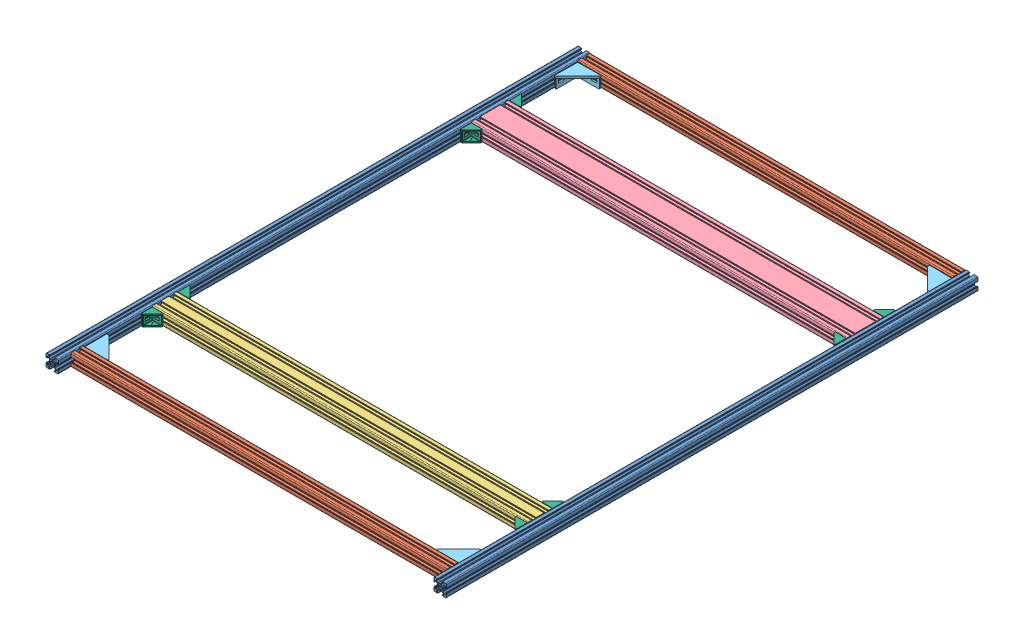
SolidWorks assembly SideAluminum, configuration Default. Lengths in mm.
Overall size (640 20.19 850).
18 component instances, 6 part files, 51 mates.
Components (placement in the parent):
- Profile 20x20-850mm-1: Profile 20x20-850mm [Default] at (265.7213 429.4124 252.9994) size (20 20 850)
- Profile 20x20-600mm-1: Profile 20x20-600mm [Default] at (884.2213 429.4124 254.4994) x (0 0 1) z (-1 0 0) size (20 20 600)
- Profile 20x20-850mm-2: Profile 20x20-850mm [Default] at (902.7213 449.4124 252.9994) x (-1 0 0) z (0 0 1) size (20 20 850)
- Profile 20x20-600mm-2: Profile 20x20-600mm [Default] at (284.2213 429.4124 1081.4994) x (0 0 -1) z (1 0 0) size (20 20 600)
- Profile 20x40-600m-1: Profile 20x40-600m [Default] at (884.2213 429.4124 926.6994) x (0 0 1) z (-1 0 0) size (40 20 600)
- Profile 20x60-600mm-1: Profile 20x60-600mm [Default] at (1884.2213 429.4124 396.6994) x (0 0 1) z (-1 0 0) size (60 20 600)
- Bracket 20x40-1: Bracket 20x40 [Default] at (284.2213 438.4124 272.9994) x (0 0 -1) z (0 -1 0) size (39.5 39.5 18)
- Bracket 20x40-2: Bracket 20x40 [Default] at (884.2213 438.4124 272.9994) x (1 0 0) z (0 -1 0) size (39.5 39.5 18)
- Bracket 20x40-3: Bracket 20x40 [Default] at (284.2213 438.4124 1062.9994) x (-1 0 0) z (0 -1 0) size (39.5 39.5 18)
- Bracket 20x40-4: Bracket 20x40 [Default] at (884.2213 438.4124 1062.9994) x (0 0 1) z (0 -1 0) size (39.5 39.5 18)
- Bracket 20x20-1: Bracket 20x20 [Default] at (284.2213 439.7182 382.9994) x (0 0 1) z (0 1 0) size (19.8 19.8 18)
- Bracket 20x20-2: Bracket 20x20 [Default] at (884.2213 439.7182 382.9994) x (1 0 0) z (0 1 0) size (19.8 19.8 18)
- Bracket 20x20-3: Bracket 20x20 [Default] at (884.2213 440.6035 442.9994) x (1 0 0) z (0 -1 0) size (19.8 19.8 18)
- Bracket 20x20-4: Bracket 20x20 [Default] at (284.2213 439.2066 442.9994) x (-1 0 0) z (0 1 0) size (19.8 19.8 18)
- Bracket 20x20-5: Bracket 20x20 [Default] at (284.2213 439.7182 912.9994) x (0 0 1) z (0 1 0) size (19.8 19.8 18)
- Bracket 20x20-6: Bracket 20x20 [Default] at (284.2213 439.2066 952.9994) x (0 0 -1) z (0 -1 0) size (19.8 19.8 18)
- Bracket 20x20-7: Bracket 20x20 [Default] at (884.2213 439.7182 912.9994) x (1 0 0) z (0 1 0) size (19.8 19.8 18)
- Bracket 20x20-8: Bracket 20x20 [Default] at (884.2213 440.1188 952.9994) x (1 0 0) z (0 -1 0) size (19.8 19.8 18)
Mates (geometry in assembly coordinates):
- Coincident1: coincident anti-aligned: plane of Profile 20x20-850mm-1 through (284.2213 447.9124 252.9994) normal (1 0 0); plane of Profile 20x20-600mm-1 through (284.2213 439.4124 262.9994) normal (-1 0 0)
- Coincident2: coincident aligned: plane of Profile 20x20-850mm-1 through (278.0713 449.4124 252.9994) normal (0 1 0); plane of Profile 20x20-600mm-1 through (884.2213 449.4124 254.4994) normal (0 1 0)
- Coincident3: coincident aligned: plane of Profile 20x20-850mm-1 through (274.2213 439.4124 252.9994) normal (0 0 -1); plane of Profile 20x20-600mm-1 through (884.2213 443.2624 252.9994) normal (0 0 -1)
- Coincident4: coincident anti-aligned: plane of Profile 20x20-600mm-1 through (884.2213 439.4124 262.9994) normal (1 0 0); plane of Profile 20x20-850mm-2 through (884.2213 430.9124 252.9994) normal (-1 0 0)
- Coincident5: coincident aligned: plane of Profile 20x20-600mm-1 through (884.2213 443.2624 252.9994) normal (0 0 -1); plane of Profile 20x20-850mm-2 through (894.2213 439.4124 252.9994) normal (0 0 -1)
- Coincident6: coincident aligned: plane of Profile 20x20-600mm-1 through (884.2213 449.4124 266.8494) normal (0 1 0); plane of Profile 20x20-850mm-2 through (885.7213 449.4124 252.9994) normal (0 1 0)
- Coincident7: coincident anti-aligned: plane of Profile 20x20-850mm-1 through (284.2213 447.9124 252.9994) normal (1 0 0); plane of Profile 20x20-600mm-2 through (284.2213 439.4124 1072.9994) normal (-1 0 0)
- Coincident8: coincident aligned: plane of Profile 20x20-850mm-1 through (278.0713 449.4124 252.9994) normal (0 1 0); plane of Profile 20x20-600mm-2 through (284.2213 449.4124 1069.1494) normal (0 1 0)
- Distance1: distance = 20 mm aligned: plane of Profile 20x20-600mm-2 through (284.2213 443.2624 1082.9994) normal (0 0 1); plane of Profile 20x20-850mm-1 through (274.2213 439.4124 1102.9994) normal (0 0 1)
- Coincident10: coincident anti-aligned: plane of Profile 20x20-850mm-1 through (284.2213 447.9124 252.9994) normal (1 0 0); plane of Profile 20x40-600m-1 through (284.2213 439.4124 932.9994) normal (-1 0 0)
- Coincident11: coincident aligned: plane of Profile 20x20-850mm-1 through (278.0713 449.4124 252.9994) normal (0 1 0); plane of Profile 20x40-600m-1 through (884.2213 449.4124 926.6994) normal (0 1 0)
- Distance2: distance = 110 mm anti-aligned: plane of Profile 20x40-600m-1 through (884.2213 447.9124 952.9994) normal (0 0 1); plane of Profile 20x20-600mm-2 through (284.2213 447.9124 1062.9994) normal (0 0 -1)
- Coincident13: coincident anti-aligned: plane of Profile 20x20-850mm-1 through (284.2213 447.9124 252.9994) normal (1 0 0); plane of Profile 20x60-600mm-1 through (284.2213 439.4124 422.9994) normal (-1 0 0)
- Coincident14: coincident aligned: plane of Profile 20x20-850mm-1 through (278.0713 449.4124 252.9994) normal (0 1 0); plane of Profile 20x60-600mm-1 through (884.2213 449.4124 439.2994) normal (0 1 0)
- Distance3: distance = 110 mm anti-aligned: plane of Profile 20x20-600mm-1 through (884.2213 435.5624 272.9994) normal (0 0 1); plane of Profile 20x60-600mm-1 through (884.2213 435.7124 382.9994) normal (0 0 -1)
- Coincident20: coincident: line of Profile 20x20-850mm-1 through (284.2213 443.2624 252.9994) axis (0 0 1); plane of Bracket 20x40-1 through (284.2213 429.4124 272.9994) normal (-1 0 0)
- Coincident23: coincident anti-aligned: plane of Profile 20x20-600mm-1 through (884.2213 435.5624 272.9994) normal (0 0 1); plane of Bracket 20x40-1 through (284.2213 429.4124 272.9994) normal (0 0 -1)
- Coincident27: coincident aligned: plane of Profile 20x20-600mm-1 through (884.2213 429.4124 271.4994) normal (0 -1 0); plane of Bracket 20x40-1 through (284.2213 429.4124 310.9994) normal (0 -1 0)
- Coincident28: coincident anti-aligned: plane of Profile 20x20-850mm-2 through (884.2213 443.2624 252.9994) normal (-1 0 0); plane of Bracket 20x40-2 through (884.2213 429.4124 272.9994) normal (1 0 0)
- Coincident29: coincident anti-aligned: plane of Profile 20x20-600mm-1 through (884.2213 447.9124 272.9994) normal (0 0 1); plane of Bracket 20x40-2 through (884.2213 429.4124 272.9994) normal (0 0 -1)
- Coincident30: coincident aligned: plane of Profile 20x20-600mm-1 through (884.2213 429.4124 271.4994) normal (0 -1 0); plane of Bracket 20x40-2 through (846.2213 429.4124 272.9994) normal (0 -1 0)
- Coincident31: coincident anti-aligned: plane of Profile 20x20-850mm-1 through (284.2213 447.9124 252.9994) normal (1 0 0); plane of Bracket 20x40-3 through (284.2213 429.4124 1062.9994) normal (-1 0 0)
- Coincident32: coincident anti-aligned: plane of Profile 20x20-600mm-2 through (284.2213 447.9124 1062.9994) normal (0 0 -1); plane of Bracket 20x40-3 through (284.2213 429.4124 1062.9994) normal (0 0 1)
- Coincident33: coincident aligned: plane of Profile 20x20-600mm-2 through (284.2213 429.4124 1064.4994) normal (0 -1 0); plane of Bracket 20x40-3 through (322.2213 429.4124 1062.9994) normal (0 -1 0)
- Coincident34: coincident anti-aligned: plane of Profile 20x20-600mm-2 through (284.2213 447.9124 1062.9994) normal (0 0 -1); plane of Bracket 20x40-4 through (884.2213 429.4124 1062.9994) normal (0 0 1)
- Coincident35: coincident anti-aligned: plane of Profile 20x20-850mm-2 through (884.2213 443.2624 252.9994) normal (-1 0 0); plane of Bracket 20x40-4 through (884.2213 429.4124 1062.9994) normal (1 0 0)
- Coincident36: coincident aligned: plane of Profile 20x20-600mm-2 through (284.2213 429.4124 1064.4994) normal (0 -1 0); plane of Bracket 20x40-4 through (884.2213 429.4124 1024.9994) normal (0 -1 0)
- Coincident37: coincident anti-aligned: plane of Profile 20x20-850mm-1 through (284.2213 447.9124 252.9994) normal (1 0 0); plane of Bracket 20x20-1 through (284.2213 448.7182 392.5751) normal (-1 0 0)
- Coincident38: coincident anti-aligned: plane of Profile 20x60-600mm-1 through (884.2213 447.9124 392.9994) normal (0 0 -1); plane of Bracket 20x20-1 through (301.5454 448.7182 392.9994) normal (0 0 1)
- Tangent1: tangent aligned: cylinder of Profile 20x20-850mm-1 through (283.5213 442.7124 252.9994) axis (0 0 1) radius 0.2; plane of Bracket 20x20-1 through (287.2213 442.3182 378.9994) normal (-0.052336 -0.99863 0)
- Coincident40: coincident anti-aligned: plane of Profile 20x20-850mm-2 through (884.2213 443.2624 252.9994) normal (-1 0 0); plane of Bracket 20x20-2 through (884.2213 448.7182 375.6753) normal (1 0 0)
- Coincident41: coincident anti-aligned: plane of Profile 20x60-600mm-1 through (884.2213 435.7124 392.9994) normal (0 0 -1); plane of Bracket 20x20-2 through (883.7971 448.7182 392.9994) normal (0 0 1)
- Tangent2: tangent aligned: cylinder of Profile 20x20-850mm-2 through (884.9213 442.7124 252.9994) axis (0 0 1) radius 0.2; plane of Bracket 20x20-2 through (881.2213 442.3182 378.9994) normal (0.052336 -0.99863 0)
- Coincident42: coincident anti-aligned: plane of Profile 20x60-600mm-1 through (884.2213 443.1124 452.9994) normal (0 0 1); plane of Bracket 20x20-3 through (883.7971 431.6035 452.9994) normal (0 0 -1)
- Coincident43: coincident anti-aligned: plane of Profile 20x20-850mm-2 through (884.2213 443.2624 252.9994) normal (-1 0 0); plane of Bracket 20x20-3 through (884.2213 431.6035 470.3235) normal (1 0 0)
- Tangent3: tangent anti-aligned: cylinder of Profile 20x60-600mm-1 through (884.2213 442.9124 451.9994) axis (-1 0 0) radius 0.5; plane of Bracket 20x20-3 through (870.2213 443.2035 455.9994) normal (0 -0.99863 -0.052336)
- Coincident45: coincident anti-aligned: plane of Profile 20x20-850mm-1 through (284.2213 447.9124 252.9994) normal (1 0 0); plane of Bracket 20x20-4 through (284.2213 448.2066 470.3235) normal (-1 0 0)
- Coincident46: coincident anti-aligned: plane of Profile 20x60-600mm-1 through (884.2213 443.1124 452.9994) normal (0 0 1); plane of Bracket 20x20-4 through (284.6456 448.2066 452.9994) normal (0 0 -1)
- Tangent4: tangent aligned: cylinder of Profile 20x60-600mm-1 through (884.2213 436.2124 452.2994) axis (-1 0 0) radius 0.2; plane of Bracket 20x20-4 through (298.2213 436.6066 455.9994) normal (0 0.99863 -0.052336)
- Coincident48: coincident anti-aligned: plane of Profile 20x20-850mm-1 through (284.2213 447.9124 252.9994) normal (1 0 0); plane of Bracket 20x20-6 through (284.2213 430.2066 953.4237) normal (-1 0 0)
- Coincident49: coincident anti-aligned: plane of Profile 20x40-600m-1 through (884.2213 447.9124 952.9994) normal (0 0 1); plane of Bracket 20x20-6 through (301.5454 430.2066 952.9994) normal (0 0 -1)
- Tangent5: tangent aligned: cylinder of Profile 20x40-600m-1 through (884.2213 436.2124 952.2994) axis (-1 0 0) radius 0.2; plane of Bracket 20x20-6 through (298.2213 436.6066 955.9994) normal (0 0.99863 -0.052336)
- Coincident51: coincident anti-aligned: plane of Profile 20x40-600m-1 through (884.2213 443.1124 912.9994) normal (0 0 -1); plane of Bracket 20x20-5 through (301.5454 448.7182 912.9994) normal (0 0 1)
- Coincident52: coincident anti-aligned: plane of Profile 20x20-850mm-1 through (284.2213 435.5624 252.9994) normal (1 0 0); plane of Bracket 20x20-5 through (284.2213 448.7182 912.5751) normal (-1 0 0)
- Tangent6: tangent aligned: cylinder of Profile 20x20-850mm-1 through (283.5213 442.7124 252.9994) axis (0 0 1) radius 0.2; plane of Bracket 20x20-5 through (287.2213 442.3182 898.9994) normal (-0.052336 -0.99863 0)
- Coincident54: coincident: plane of Profile 20x40-600m-1 through (884.2213 430.9124 912.9994) normal (0 0 -1); plane of Bracket 20x20-7 through (883.7971 448.7182 912.9994) normal (0 0 1)
- Coincident55: coincident: plane of Profile 20x20-850mm-2 through (884.2213 430.9124 252.9994) normal (-1 0 0); plane of Bracket 20x20-7 through (884.2213 448.7182 895.6753) normal (1 0 0)
- Tangent7: tangent aligned: cylinder of Profile 20x20-850mm-2 through (884.9213 442.7124 252.9994) axis (0 0 1) radius 0.2; plane of Bracket 20x20-7 through (881.2213 442.3182 898.9994) normal (0.052336 -0.99863 0)
- Coincident58: coincident: plane of Profile 20x20-850mm-2 through (884.2213 443.2624 252.9994) normal (-1 0 0); plane of Bracket 20x20-8 through (884.2213 431.1188 970.3235) normal (1 0 0)
- Coincident59: coincident: plane of Profile 20x40-600m-1 through (884.2213 435.7124 952.9994) normal (0 0 1); plane of Bracket 20x20-8 through (883.7971 431.1188 952.9994) normal (0 0 -1)
- Tangent8: tangent anti-aligned: cylinder of Profile 20x20-850mm-2 through (884.9213 442.7124 252.9994) axis (0 0 1) radius 0.2; plane of Bracket 20x20-8 through (881.2213 442.7188 966.9994) normal (0.052336 -0.99863 0)
